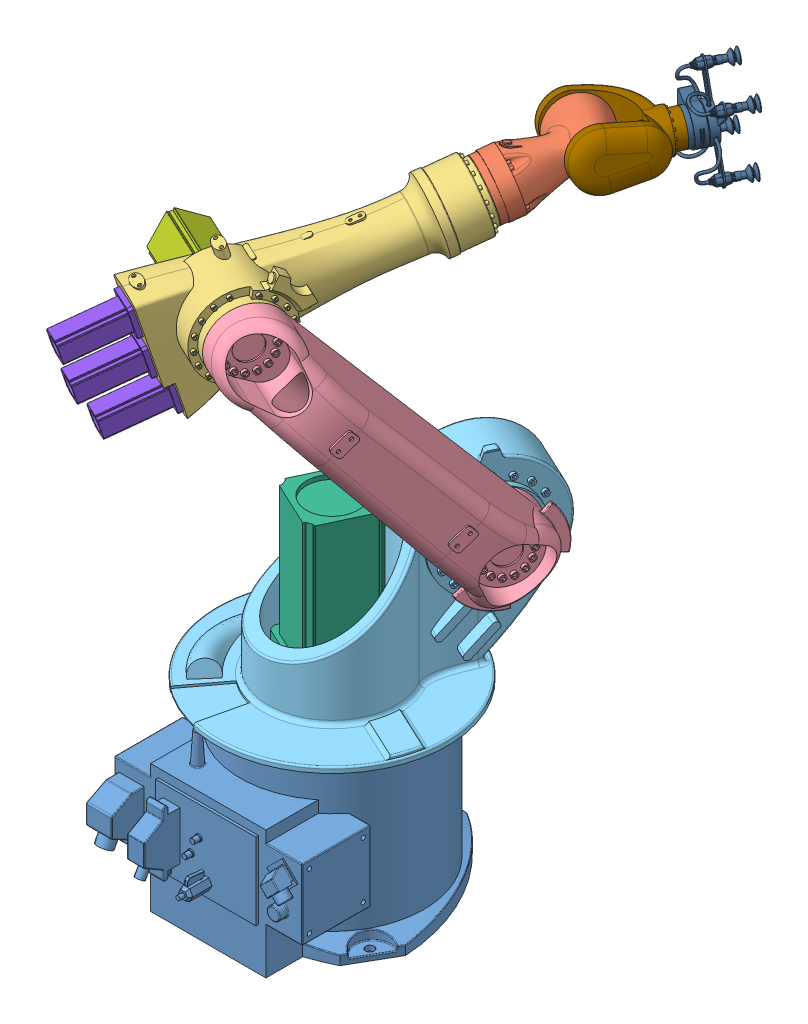
SolidWorks assembly Aassembly, configuration Default. Lengths in mm.
Overall size (774.8 1490.78 1152.45).
12 component instances, 10 part files, 27 mates.
Components (placement in the parent):
- Part6-1: Part6 [Default] at (112.7676 103.039 544.6226) size (551.25 397.79 640.74)
- Part2-1: Part2 [Default] at (212.559 1379.4927 288.2352) x (-0.329465 0.932786 0.146159) z (-0.406025 -0.27973 0.869997) size (134.02 143.08 255.16)
- Part3-1: Part3 [Default] at (159.7758 1343.1278 401.3348) x (0.406025 0.27973 -0.869997) z (0.906173 0 0.422908) size (623.51 290.86 209)
- Part4-1: Part4 [Default] at (324.9977 753.335 361.7999) x (0.31996 0.653912 -0.685584) z (0.906173 0 0.422908) size (230 851.91 199)
- Part5-1: Part5 [Default] at (112.7676 466.039 544.6226) x (0.422908 0 -0.906173) z (0 1 0) size (675 540 469.21)
- Servomotor1-1: Servomotor1 [Default] at (112.7676 509.039 544.6226) x (0.906173 0 0.422908) z (-0.422908 0 0.906173) size (165 330 165)
- Servomotor2-1: Servomotor2 [Default] at (-15.2916 1267.8016 693.6947) x (0.370754 -0.481079 -0.794421) z (0.203452 0.876677 -0.435941) size (113.13 165 113.13)
- Servomotor3-1: Servomotor3 [Default] at (-20.4873 1115.4519 787.1073) x (-0.906173 0 -0.422908) z (-0.1183 0.960079 0.253484) size (70 140 70)
- Servomotor3-2: Servomotor3 [Default] at (-40.3598 1197.1179 828.2289) x (-0.906173 0 -0.422908) z (-0.1183 0.960079 0.253484) size (70 140 70)
- Part1-2: Part1 [Default] at (347.6673 1448.0972 154.9566) x (0.474551 0.041869 -0.879232) z (0.852406 0.22729 0.470896) size (217.6 134.01 237.35)
- Servomotor3-3: Servomotor3 [Default] at (-51.0068 1283.525 851.0425) x (-0.906173 0 -0.422908) z (-0.1183 0.960079 0.253484) size (70 140 70)
- Vacuum gripper-1: Vacuum gripper [Default] at (380.8784 1443.5753 -7.0359) x (0.868907 -0.181971 0.460312) z (-0.140722 -0.982412 -0.122735) size (159.22 116.4 195.83)
Mates (geometry in assembly coordinates):
- Concentric1: concentric aligned: cylinder of Part6-1 through (112.7676 466.039 544.6226) axis (0 -1 0) radius 215; cylinder of Part5-1 through (112.7676 879.039 544.6226) axis (0 -1 0) radius 150
- Coincident1: coincident anti-aligned: plane of Part6-1 through (112.7676 466.039 544.6226) normal (0 1 0); plane of Part5-1 through (112.7676 466.039 544.6226) normal (0 -1 0)
- Concentric2: concentric anti-aligned: cylinder of Part4-1 through (336.9014 748.039 362.304) axis (0.906173 0 0.422908) radius 30; cylinder of Part5-1 through (290.6866 748.039 340.7357) axis (-0.906173 0 -0.422908) radius 95
- Coincident3: coincident anti-aligned: plane of Part4-1 through (253.814 848.915 419.7433) normal (-0.906173 0 -0.422908); plane of Part5-1 through (290.6866 748.039 340.7357) normal (0.906173 0 0.422908)
- Concentric3: concentric anti-aligned: cylinder of Part3-1 through (113.3869 1267.803 753.7433) axis (0.906173 0 0.422908) radius 80; cylinder of Part4-1 through (562.8486 1267.803 963.5056) axis (-0.906173 0 -0.422908) radius 80
- Coincident4: coincident anti-aligned: plane of Part3-1 through (134.2289 1267.803 763.4702) normal (0.906173 0 0.422908); plane of Part4-1 through (134.2289 1267.803 763.4702) normal (-0.906173 0 -0.422908)
- Concentric4: concentric anti-aligned: cylinder of Part2-1 through (218.6494 1383.6887 275.1852) axis (-0.406025 -0.27973 0.869997) radius 64; cylinder of Part3-1 through (212.559 1379.4927 288.2352) axis (0.406025 0.27973 -0.869997) radius 64
- Coincident5: coincident anti-aligned: plane of Part2-1 through (212.559 1379.4927 288.2352) normal (-0.406025 -0.27973 0.869997); plane of Part3-1 through (204.9878 1440.9377 304.4581) normal (0.406025 0.27973 -0.869997)
- Concentric5: concentric: cylinder of ? through (511.243 1494.7793 554.6108) axis (-0.112336 0.590134 0.799451) radius 51.5; cylinder of Part2-1 through (236.8545 1418.5495 93.7402) axis (-0.852406 -0.22729 -0.470896) radius 51.5
- Coincident7: coincident: plane of ? through (527.644 1408.6197 437.8909) normal (-0.112336 0.590134 0.799451); plane of Part2-1 through (344.2577 1447.188 153.0731) normal (0.852406 0.22729 0.470896)
- Concentric6: concentric aligned: cylinder of Part2-1 through (236.8545 1418.5495 93.7402) axis (-0.852406 -0.22729 -0.470896) radius 51.5; cylinder of Part1-2 through (224.0684 1415.1401 86.6768) axis (-0.852406 -0.22729 -0.470896) radius 51.5
- Coincident8: coincident anti-aligned: plane of Part2-1 through (224.0684 1415.1401 86.6768) normal (-0.852406 -0.22729 -0.470896); plane of Part1-2 through (224.0684 1415.1401 86.6768) normal (0.852406 0.22729 0.470896)
- Coincident12: coincident aligned: plane of Part5-1 through (143.5753 509.039 650.0426) normal (-0.422908 0 0.906173); plane of Servomotor1-1 through (12.1802 539.039 588.721) normal (-0.422908 0 0.906173)
- Coincident13: coincident aligned: plane of Part5-1 through (7.3476 509.039 575.4302) normal (-0.906173 0 -0.422908); plane of Servomotor1-1 through (7.3476 539.039 575.4302) normal (-0.906173 0 -0.422908)
- Coincident14: coincident anti-aligned: plane of Part5-1 through (112.7676 509.039 544.6226) normal (0 1 0); plane of Servomotor1-1 through (112.7676 509.039 544.6226) normal (0 -1 0)
- Parallel4: parallel anti-aligned: plane of Part3-1 through (-66.6597 1335.8425 699.7206) normal (0.370754 -0.481079 -0.794421); plane of Servomotor2-1 through (-189.5135 1258.1473 676.8473) normal (-0.370754 0.481079 0.794421)
- Coincident17: coincident anti-aligned: plane of Part3-1 through (-66.6597 1335.8425 699.7206) normal (0.370754 -0.481079 -0.794421); plane of Servomotor2-1 through (-40.3821 1335.8363 711.988) normal (-0.370754 0.481079 0.794421)
- Coincident18: coincident anti-aligned: plane of Part3-1 through (-49.4047 1195.8075 662.7479) normal (0.203452 0.876677 -0.435941); plane of Servomotor2-1 through (-57.6566 1240.6137 749.0023) normal (-0.203452 -0.876677 0.435941)
- Coincident19: coincident anti-aligned: plane of Part3-1 through (128.0597 1343.1278 386.533) normal (-0.906173 0 -0.422908); plane of Servomotor2-1 through (-15.2916 1267.8016 693.6947) normal (0.906173 0 0.422908)
- Coincident20: coincident anti-aligned: plane of Part3-1 through (-32.0709 1210.9552 812.4084) normal (-0.406025 -0.27973 0.869997); plane of Servomotor3-1 through (-20.4873 1115.4519 787.1073) normal (0.406025 0.27973 -0.869997)
- Distance1: distance = 10 mm anti-aligned: plane of Part3-1 through (-95.573 1158.6555 765.9563) normal (0.1183 -0.960079 -0.253484); plane of Servomotor3-1 through (-1.5029 1146.2574 817.3664) normal (-0.1183 0.960079 0.253484)
- Distance2: distance = 20 mm: line of Part3-1 through (-8.4697 1323.0831 883.6135) axis (0.1183 -0.960079 -0.253484); line of Servomotor3-1 through (3.6195 1141.457 818.2135) axis (0.1183 -0.960079 -0.253484)
- Coincident23: coincident anti-aligned: plane of Part3-1 through (-62.2438 1075.5577 778.9304) normal (-0.406025 -0.27973 0.869997); plane of Servomotor3-2 through (-40.3598 1197.1179 828.2289) normal (0.406025 0.27973 -0.869997)
- Distance3: distance = 15 mm: line of Servomotor3-2 through (-13.0943 1160.7179 840.7442) axis (-0.906173 0 -0.422908); line of Part3-1 through (-80.821 1152.7812 795.0902) axis (0.906173 0 0.422908)
- Distance4: distance = 20 mm: line of Servomotor3-2 through (-16.253 1223.123 859.3352) axis (0.1183 -0.960079 -0.253484); line of Part3-1 through (-8.4697 1323.0831 883.6135) axis (0.1183 -0.960079 -0.253484)
- Concentric7: concentric anti-aligned: cylinder of Part1-2 through (369.0147 1442.5286 14.9449) axis (0.474551 0.041869 -0.879232) radius 37.5; cylinder of Vacuum gripper-1 through (385.6239 1443.994 -15.8282) axis (-0.474551 -0.041869 0.879232) radius 37.5
- Coincident24: coincident anti-aligned: plane of Part1-2 through (380.8784 1443.5753 -7.0359) normal (0.474551 0.041869 -0.879232); plane of Vacuum gripper-1 through (380.8784 1443.5753 -7.0359) normal (-0.474551 -0.041869 0.879232)
